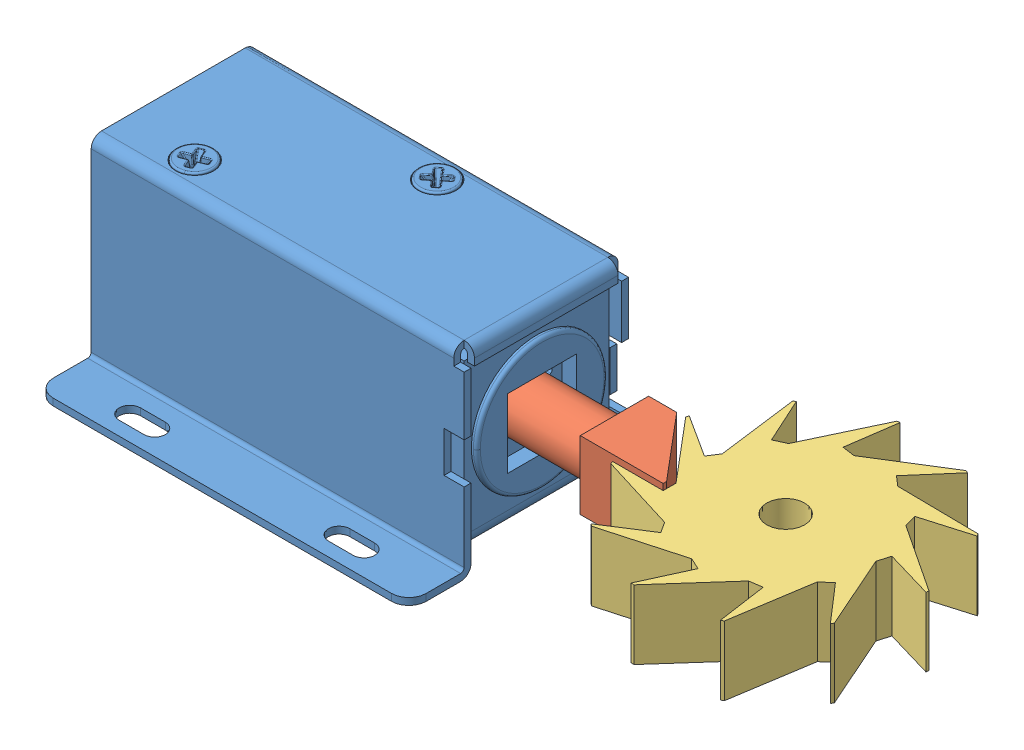
SolidWorks assembly Assem1, configuration Default. Lengths in mm.
Overall size (109.27 28.79 39.8).
3 component instances, 3 part files, 5 mates.
Components (placement in the parent):
- lock-1: lock [Default] at (-0.2244 -2.9205 4.0091) size (54.62 28.79 39.8)
- lockrod-1: lockrod [Default] at (12.338 -7.157 74.8627) x (1 0 0) z (0 1 0) size (42 9.9 9.9)
- Part2^Assem1-1: Part2^Assem1 [Default] at (80.8353 35.438 41.5541) x (1 0 0) z (0 -1 0) size (39.38 39.64 10) (virtual)
Mates (geometry in assembly coordinates):
- Concentric2: concentric anti-aligned: cylinder of lock-1 through (0.5793 30.388 41.5541) axis (1 0 0) radius 3.85; cylinder of lockrod-1 through (55.0417 30.388 41.5541) axis (-1 0 0) radius 3.85
- LimitDistance1: limit distance = 10.4624 mm anti-aligned: plane of lockrod-1 through (56.0417 25.438 46.5041) normal (-1 0 0); plane of lock-1 through (45.5793 21.3306 32.4967) normal (1 0 0)
- Parallel1: parallel aligned: plane of lock-1 through (-7.8207 17.338 53.4541) normal (0 0 1); plane of lockrod-1 through (56.0417 25.438 46.5041) normal (0 0 1)
- Coincident2: coincident aligned: plane of lockrod-1 through (56.0417 25.438 46.5041) normal (0 -1 0); plane of Part2^Assem1-1 through (80.8353 25.438 41.5541) normal (0 -1 0)
- Coincident3: coincident anti-aligned: plane of lockrod-1; plane of Part2^Assem1-1 through (80.8353 35.438 41.5541) normal (0 0 1)
